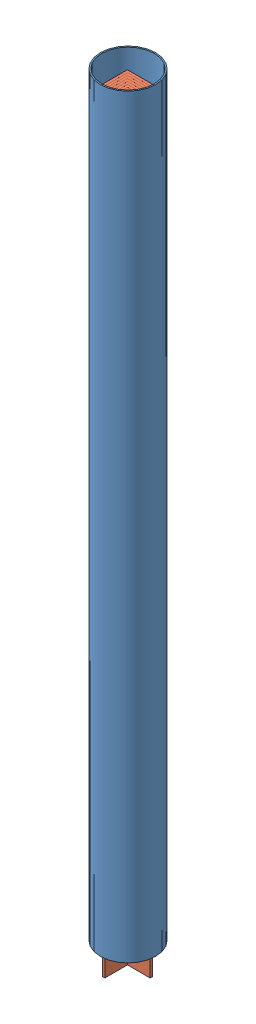
SolidWorks assembly Сборка1, configuration По умолчанию. Lengths in mm.
Overall size (110 1539.04 110).
9 component instances, 2 part files, 4 mates.
Components (placement in the parent):
- Труба 110-1: Труба 110 [По умолчанию] at origin size (110 1500 110)
- Ребро1500H5-1: Ребро1500H5 [По умолчанию] at (-37.498 -39.0445 -36.458) x (0 0 1) z (-1 0 0) size (50 1500 50)
- Ребро1500H5-2: Ребро1500H5 [По умолчанию] at (-32.4776 -39.0445 -31.4376) x (0 0 1) z (-1 0 0) size (50 1500 50)
- Ребро1500H5-3: Ребро1500H5 [По умолчанию] at (-27.4571 -39.0445 -26.4171) x (0 0 1) z (-1 0 0) size (50 1500 50)
- Ребро1500H5-4: Ребро1500H5 [По умолчанию] at (-22.4367 -39.0445 -21.3966) x (0 0 1) z (-1 0 0) size (50 1500 50)
- Ребро1500H5-5: Ребро1500H5 [По умолчанию] at (-17.4162 -39.0445 -16.3762) x (0 0 1) z (-1 0 0) size (50 1500 50)
- Ребро1500H5-6: Ребро1500H5 [По умолчанию] at (-12.3957 -39.0445 -11.3557) x (0 0 1) z (-1 0 0) size (50 1500 50)
- Ребро1500H5-7: Ребро1500H5 [По умолчанию] at (-7.3753 -39.0445 -6.3353) x (0 0 1) z (-1 0 0) size (50 1500 50)
- Ребро1500H5-8: Ребро1500H5 [По умолчанию] at (-2.3548 -39.0445 -1.3148) x (0 0 1) z (-1 0 0) size (50 1500 50)
Mates (geometry in assembly coordinates):
- Параллельность1: parallel aligned: cylinder of Труба 110-1 through (0 1500 0) axis (0 -1 0) radius 52.3; line of Ребро1500H5-1 through (-37.498 1460.9555 -36.458) axis (0 -1 0)
- Совпадение3: coincident: cylinder of Труба 110-1 through (0 1500 0) axis (0 -1 0) radius 52.3; line of Ребро1500H5-1 through (-37.498 1460.9555 -36.458) axis (0 -1 0)
- Параллельность2: parallel anti-aligned: plane of Ребро1500H5-1 through (-37.498 1460.9555 -36.458) normal (-1 0 0)
- Параллельность3: parallel anti-aligned: plane of Ребро1500H5-1 through (-37.498 1460.9555 -36.458) normal (0 0 -1)
